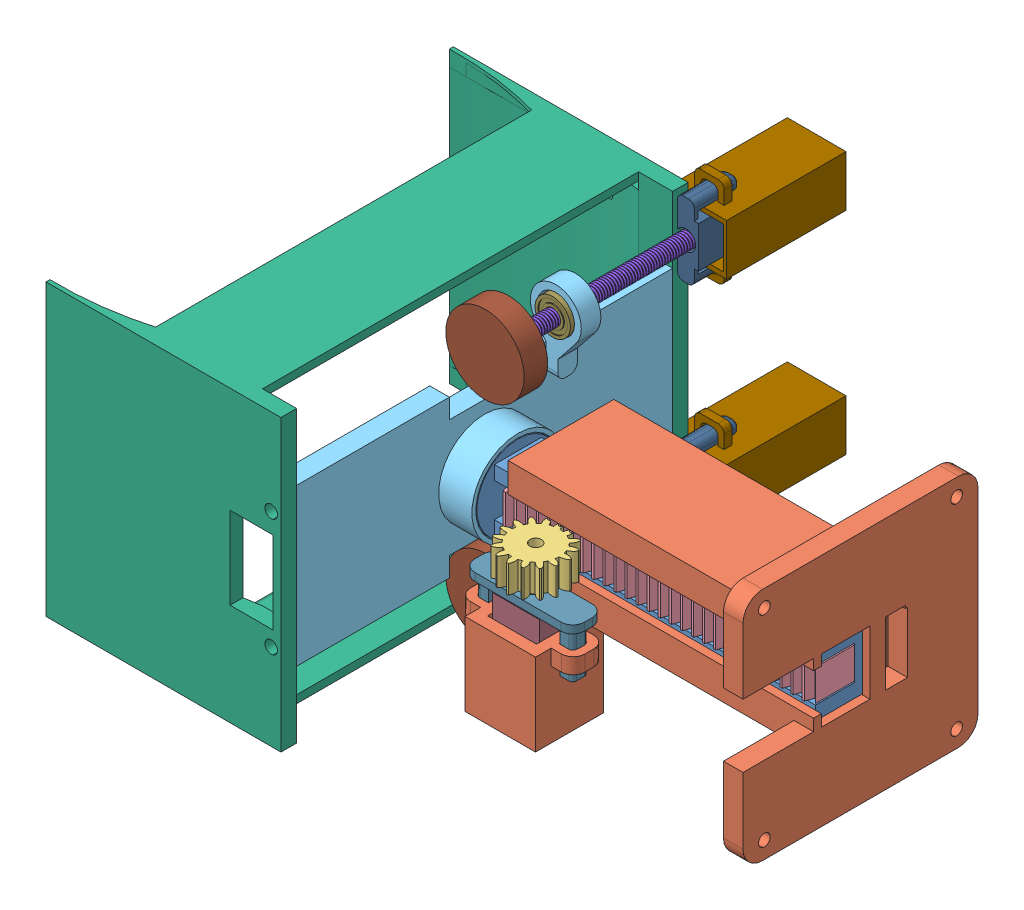
SolidWorks assembly 1, configuration Default. Lengths in mm.
Overall size (152.39 137.84 144.65).
23 component instances, 14 part files, 20 mates.
Components (placement in the parent):
- rack platform V3-1: rack platform V3 [Default] at (74.2988 -233.9108 -214.7311) x (0 1 0) z (1 0 0) size (21 21 94)
- rack base V5-1: rack base V5 [Default] at (75.6923 -247.0108 -212.3311) x (0 0 -1) z (0 1 0) size (60 80.6 64)
- spur gear_am-1: spur gear_am [Metric - Spur gear 0.9M 16T 20PA 7FW ---S16N75H50L3N] at (51.4423 -230.5108 -195.1382) x (0 -1 0) z (-0.995823 0 -0.09131) size (7 15.96 15.96)
- rack spur rectangular_am-1: rack spur rectangular_am [Metric - Rack-spur - rectangular 0.9M 20PA 8FW 10PH 80L---SAll] at (35.2988 -237.9108 -212.7311) x (1 0 0) z (0 -1 0) size (80 10.9 8)
- poker case assembly 2-1: poker case assembly 2 [Default] at (106.031 -207.2338 -272.3389) x (0 -1 0) z (-1 0 0) size (137.84 144.65 92.58)
  - poker case base 1-1: poker case base 1 [Default] at (25.1895 51.145 81.2322) size (67.62 96 14)
  - poker case base 2-1: poker case base 2 [Default] at (26.6771 63.6078 81.2322) size (74.12 104 60)
  - Motor& Roller Assembly-1: Motor& Roller Assembly [Default] at (50.9792 46.5267 41.0782) x (0.457967 -0.029593 -0.888476) z (-0.261122 0.950879 -0.166268) size (38.09 49.96 91.68)
    - M4 Nut-1: M4 Nut [Default] at (-57.6078 23.6231 20.5659) x (-0.029593 -0.308146 0.950879) z (-0.746697 -0.625603 -0.225974) size (3.68 8.08 7)
    - New Motor-1: New Motor [Default] at (-55.0798 47.2645 -54.1441) x (0.888476 0.427744 0.166268) z (-0.029593 -0.308146 0.950879) size (12 10.57 80.84)
    - New Motor case2-1: New Motor case2 [Default] at (-61.0264 35.7877 -27.0245) x (0.457967 -0.849754 -0.261122) z (0.029593 0.308146 -0.950879) size (23 30 30.5)
    - New Motor enclosure-1: New Motor enclosure [Default] at (-56.0797 37.2316 -23.2476) x (0.457967 -0.849754 -0.261122) z (0.029593 0.308146 -0.950879) size (18.9 5.4 12)
    - New Motor roller-1: New Motor roller [Default] at (-57.4381 24.395 18.2973) x (0.972856 0.20955 0.098185) z (-0.029593 -0.308146 0.950879) size (20 20 8)
    - Bearing-1: Bearing [Default] at (-57.0267 27.371 7.1805) x (0.911456 -0.398837 -0.100882) z (0.410332 0.863699 0.292664) size (9 4 9)
  - Motor& Roller Assembly-2: Motor& Roller Assembly [Default] at (104.9792 46.5267 41.0782) x (0.457967 -0.029593 -0.888476) z (-0.261122 0.950879 -0.166268) size (38.09 49.96 91.68)
    - M4 Nut-1: M4 Nut [Default] at (-57.6078 23.6231 20.5659) x (-0.029593 -0.308146 0.950879) z (-0.746697 -0.625603 -0.225974) size (3.68 8.08 7)
    - New Motor-1: New Motor [Default] at (-55.0798 47.2645 -54.1441) x (0.888476 0.427744 0.166268) z (-0.029593 -0.308146 0.950879) size (12 10.57 80.84)
    - New Motor case2-1: New Motor case2 [Default] at (-61.0264 35.7877 -27.0245) x (0.457967 -0.849754 -0.261122) z (0.029593 0.308146 -0.950879) size (23 30 30.5)
    - New Motor enclosure-1: New Motor enclosure [Default] at (-56.0797 37.2316 -23.2476) x (0.457967 -0.849754 -0.261122) z (0.029593 0.308146 -0.950879) size (18.9 5.4 12)
    - New Motor roller-1: New Motor roller [Default] at (-57.4381 24.395 18.2973) x (0.972856 0.20955 0.098185) z (-0.029593 -0.308146 0.950879) size (20 20 8)
    - Bearing-1: Bearing [Default] at (-57.0267 27.371 7.1805) x (0.911456 -0.398837 -0.100882) z (0.410332 0.863699 0.292664) size (9 4 9)
- motor-1: motor [Default] at (51.4423 -259.0108 -200.1382) x (0 1 0) z (0 0 1) size (34 12 10)
- motor enclosure-1: motor enclosure [Default] at (51.6923 -242.0108 -194.3382) x (0 0 1) z (0 1 0) size (8 28 14)
Mates (geometry in assembly coordinates):
- Coincident17: coincident anti-aligned: plane of rack platform V3-1 through (74.2988 -233.9108 -214.7311) normal (0 0 -1); plane of rack base V5-1 through (117.1923 -242.0108 -214.7311) normal (0 0 1)
- Parallel7: parallel anti-aligned: plane of rack platform V3-1 through (115.2988 -241.7608 -202.7311) normal (0 -1 0); plane of rack base V5-1 through (112.1923 -242.0108 -198.8311) normal (0 1 0)
- Width3: width anti-aligned: plane of rack base V5-1 through (112.1923 -242.0108 -198.8311) normal (0 1 0); plane of rack base V5-1 through (112.1923 -225.8108 -198.8311) normal (0 -1 0); plane of rack platform V3-1 through (115.2988 -241.7608 -202.7311) normal (0 -1 0); plane of rack platform V3-1 through (115.2988 -226.0608 -202.7311) normal (0 1 0)
- RackPinionMate1: rack pinion = 12.148 mm: line of rack platform V3-1 through (115.2988 -229.5608 -202.7311) axis (-1 0 0); circle of Spur gear 0.9M 16T-1
- Coincident26: coincident anti-aligned: plane of rack platform V3-1 through (74.2988 -233.9108 -212.7311) normal (0 0 1); plane of rack spur rectangular_am-1 through (35.2988 -229.9108 -212.7311) normal (0 0 -1)
- Width6: width anti-aligned: plane of rack platform V3-1 through (33.2988 -238.2608 -212.7311) normal (0 1 0); plane of rack platform V3-1 through (115.2988 -229.5608 -212.7311) normal (0 -1 0); plane of rack spur rectangular_am-1 through (35.2988 -237.9108 -201.8311) normal (0 -1 0); plane of rack spur rectangular_am-1 through (35.2988 -229.9108 -201.8311) normal (0 1 0)
- Coincident28: coincident aligned: plane of rack platform V3-1 through (115.2988 -226.0608 -202.7311) normal (1 0 0); plane of rack spur rectangular_am-1 through (115.2988 -229.9108 -212.7311) normal (1 0 0)
- Coincident29: coincident anti-aligned: plane of rack platform V3-1 through (21.2988 -233.9108 -208.7311) normal (-1 0 0); plane of poker case assembly 2-1/poker case base 1-1 through (21.2988 -233.9108 -208.7311) normal (1 0 0)
- Parallel9: parallel aligned: plane of rack base V5-1 through (117.1923 -221.0108 -200.3311) normal (0 0 1); plane of poker case assembly 2-1/poker case base 2-1 through (-15.2012 -270.9108 -156.7311) normal (0 0 1)
- Concentric19: concentric aligned: cylinder of rack platform V3-1 through (21.2988 -233.9108 -208.7311) axis (1 0 0) radius 10.5; cylinder of poker case assembly 2-1/poker case base 1-1 through (21.2988 -233.9108 -208.7311) axis (1 0 0) radius 10.75
- Coincident30: coincident anti-aligned: plane of rack base V5-1 through (110.6212 -267.0108 -202.3311) normal (0 1 0); plane of motor-1 through (57.4423 -267.0108 -190.1382) normal (0 -1 0)
- Coincident32: coincident anti-aligned: plane of rack base V5-1 through (57.4423 -247.0108 -200.1382) normal (-1 0 0); plane of motor-1 through (57.4423 -251.0108 -190.1382) normal (1 0 0)
- Concentric20: concentric anti-aligned: cylinder of spur gear_am-1 through (51.4423 -280.5109 -195.1382) axis (0 1 0) radius 1.5; cylinder of motor-1 through (51.4423 -233.0108 -195.1382) axis (0 -1 0) radius 1.5
- Distance1: distance = 4.5 mm anti-aligned: plane of motor-1 through (51.4423 -242.0108 -200.1382) normal (0 1 0); plane of spur gear_am-1 through (51.4423 -237.5108 -195.1382) normal (0 -1 0)
- Coincident34: coincident anti-aligned: plane of rack base V5-1 through (42.1923 -249.0108 -221.0666) normal (-1 0 0); plane of motor enclosure-1 through (42.1923 -254.0108 -194.3382) normal (1 0 0)
- Parallel10: parallel aligned: plane of rack base V5-1 through (51.1923 -247.0108 -217.7339) normal (0 1 0); plane of motor enclosure-1 through (51.6923 -240.0108 -194.3382) normal (0 1 0)
- Coincident35: coincident anti-aligned: plane of rack base V5-1 through (110.6212 -251.0108 -192.3382) normal (0 0 -1); plane of motor enclosure-1 through (51.6923 -254.0108 -192.3382) normal (0 0 1)
- Coincident36: coincident anti-aligned: plane of rack base V5-1 through (44.9423 -247.0108 -200.1382) normal (0 0 1); plane of motor-1 through (51.4423 -259.0108 -200.1382) normal (0 0 -1)
- Coincident37: coincident anti-aligned: plane of motor-1 through (51.4423 -242.0108 -200.1382) normal (0 1 0); plane of motor enclosure-1 through (51.6923 -242.0108 -194.3382) normal (0 -1 0)
- Parallel11: parallel aligned: plane of rack base V5-1 through (117.1923 -204.0108 -182.3311) normal (0 0 1); plane of poker case assembly 2-1/poker case base 2-1 through (-15.2012 -270.9108 -156.7311) normal (0 0 1)
